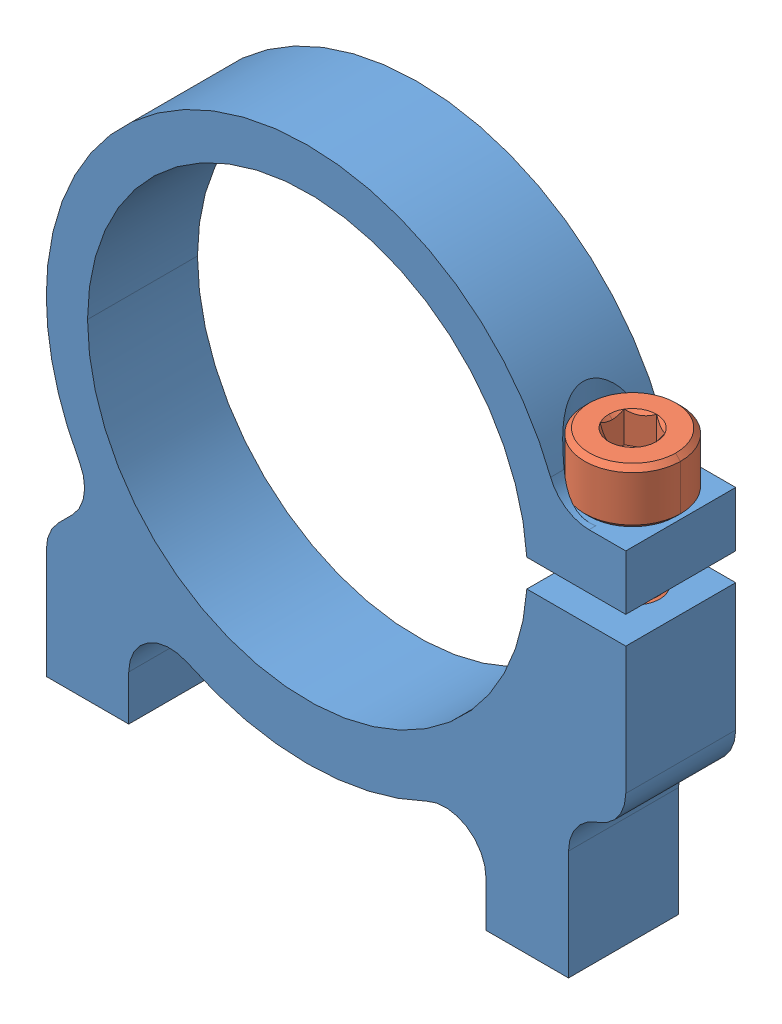
SolidWorks assembly 1-Side, 2-Post Clamping Mount (32mm Bore)1400-0032-0032, configuration Default. Lengths in mm.
Overall size (42.19 43 8).
2 component instances, 2 part files, 0 mates.
Components (placement in the parent):
- 1400-0032-0032.STEP-1: 1400-0032-0032.STEP [Default] at (-9.2052 9.5558 -4.9517) size (42.17 43 8)
- 2800-0004-0012_90128A207.STEP-1: 2800-0004-0012_90128A207.STEP [Default] at (10.4635 2.5558 -0.9517) x (0.999977 0 0.006769) z (0 -1 0) size (7 7 16.01)
